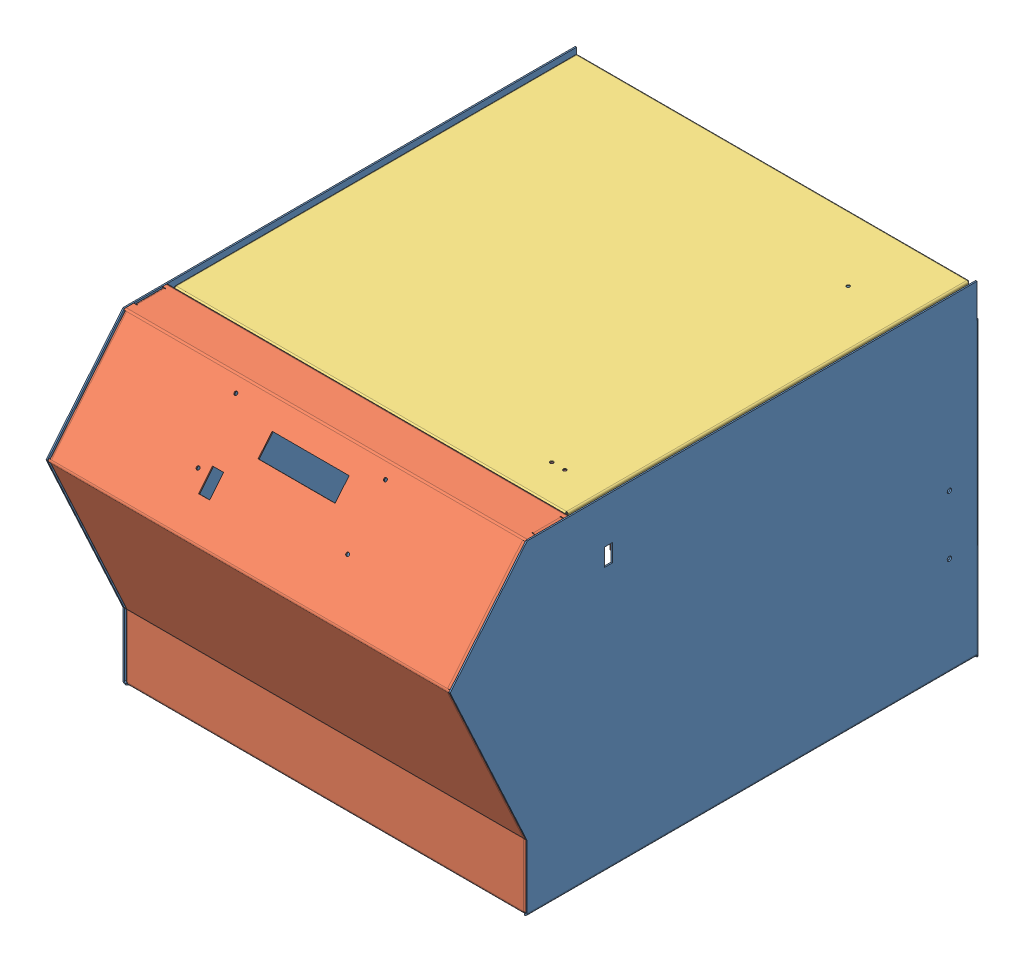
SolidWorks assembly Assem1, configuration Default. Lengths in mm.
Overall size (367.61 296 481.41).
5 component instances, 5 part files, 10 mates.
Components (placement in the parent):
- 2 nd part-1: 2 nd part [Default] at (48.3789 63.2735 540.3034) size (367.61 296 481.41)
- frt end gst-1: frt end gst [Default] at (48.5789 63.2735 540.1034) size (365 296 479.59)
- lid upper new (1)-1: lid upper new (1) [Default] at (230.9789 357.4735 316.1655) x (0 0 1) z (0 -1 0) size (367 358 29)
- Latch-1: Latch [Default] at (384.979 332.7735 465.6457) x (0 -1 0) z (-1 0 0) size (49.4 14.5 31)
- lid  down (1)-1: lid  down (1) [Default] at (1454.4238 329.2735 1343.4504) x (0 0 -1) z (0 1 0) size (363.69 358 1)
Mates (geometry in assembly coordinates):
- Coincident1: coincident anti-aligned: plane of 2 nd part-1 through (48.3789 63.2735 130.1034) normal (0 0 1); plane of frt end gst-1 through (48.5789 63.2735 130.1034) normal (0 0 -1)
- Coincident2: coincident aligned: plane of 2 nd part-1 through (414.7789 328.2735 128.9034) normal (0 1 0); plane of frt end gst-1 through (413.5789 328.2735 500.1034) normal (0 1 0)
- Coincident3: coincident anti-aligned: plane of 2 nd part-1 through (413.5789 63.2735 540.3034) normal (-1 0 0); plane of frt end gst-1 through (413.5789 63.2735 540.1034) normal (1 0 0)
- Coincident7: coincident anti-aligned: plane of lid upper new (1)-1 through (230.9789 357.4735 316.1655) normal (0 -1 0); plane of Latch-1 through (384.979 357.4735 465.6457) normal (0 1 0)
- Coincident8: coincident anti-aligned: plane of lid upper new (1)-1 through (230.9789 329.2735 316.1655) normal (0 -1 0); plane of lid  down (1)-1 through (1454.4238 329.2735 1343.4504) normal (0 1 0)
- Coincident9: coincident aligned: plane of lid upper new (1)-1 through (51.9789 357.4735 316.1655) normal (-1 0 0); plane of lid  down (1)-1 through (51.9789 328.2735 494.526) normal (-1 0 0)
- Distance3: distance = 0.0344 mm: cylinder of Latch-1 through (362.979 347.4735 466.131) axis (0 1 0) radius 2; cylinder of lid upper new (1)-1 through (362.9789 367.4735 466.1655) axis (0 -1 0) radius 1.5
- Coincident11: coincident aligned: plane of lid upper new (1)-1 through (230.9789 357.4735 132.6655) normal (0 0 -1); plane of lid  down (1)-1 through (408.5672 328.2735 132.6655) normal (0 0 -1)
- Coincident12: coincident anti-aligned: plane of frt end gst-1 through (413.5789 328.2735 500.1034) normal (0 1 0); plane of lid  down (1)-1 through (1454.4238 328.2735 1343.4504) normal (0 -1 0)
- Distance4: distance = 3.6 mm anti-aligned: plane of lid upper new (1)-1 through (51.9789 357.4735 316.1655) normal (-1 0 0); plane of 2 nd part-1 through (48.3789 63.2735 540.3034) normal (1 0 0)
